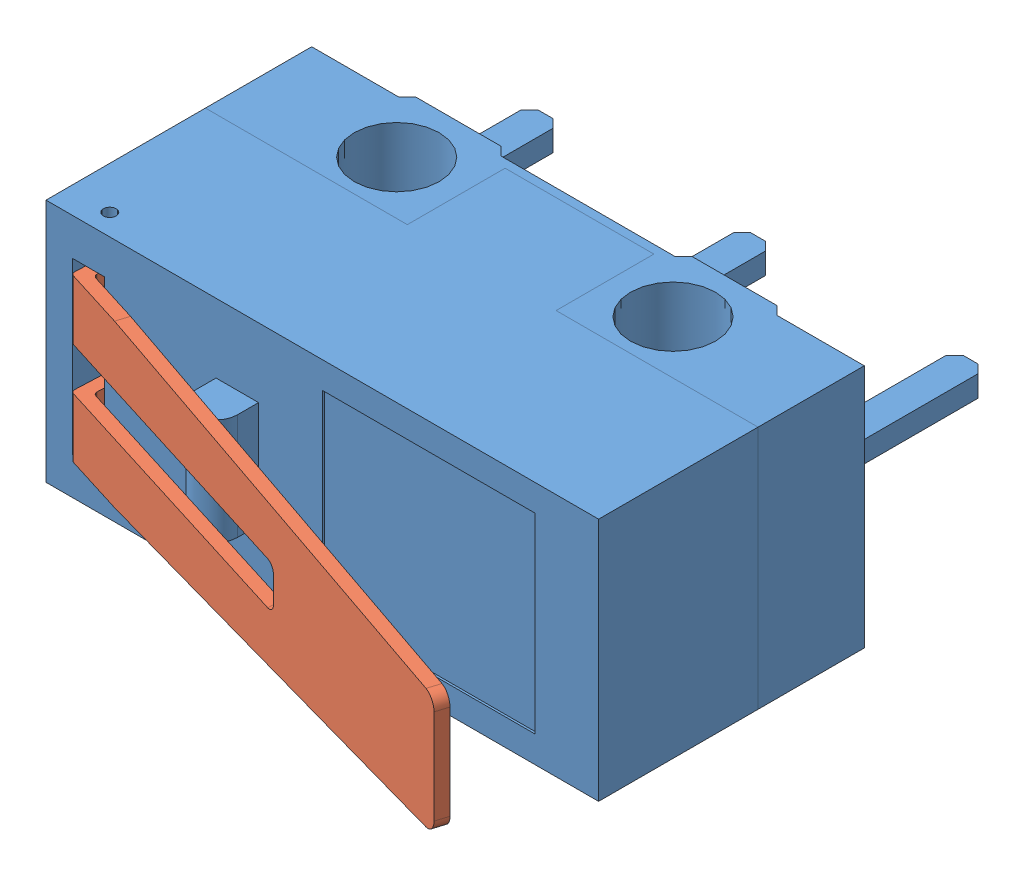
SolidWorks assembly Microsassem, configuration Default. Lengths in mm.
Overall size (13.52 5.8 14.35).
2 component instances, 2 part files, 2 mates.
Components (placement in the parent):
- Micro Switch-1: Micro Switch [Default] at (5.5673 7.1501 9.4199) size (13.05 5.8 11.25)
- Lever-1: Lever [Default] at (-0.0622 9.0501 14.6641) x (0.999157 0 0.041042) z (0 -1 0) size (12.63 4.59 4)
Mates (geometry in assembly coordinates):
- Coincident2: coincident anti-aligned: plane of Micro Switch-1 through (-0.3078 5.1501 14.4699) normal (0 1 0); plane of Lever-1 through (0.0672 5.1501 15.1699) normal (0 -1 0)
- Concentric1: concentric anti-aligned: cylinder of Micro Switch-1 through (0.0672 0.0252 15.1699) axis (0 1 0) radius 0.15; cylinder of Lever-1 through (0.0672 9.1501 15.1699) axis (0 -1 0) radius 0.15
